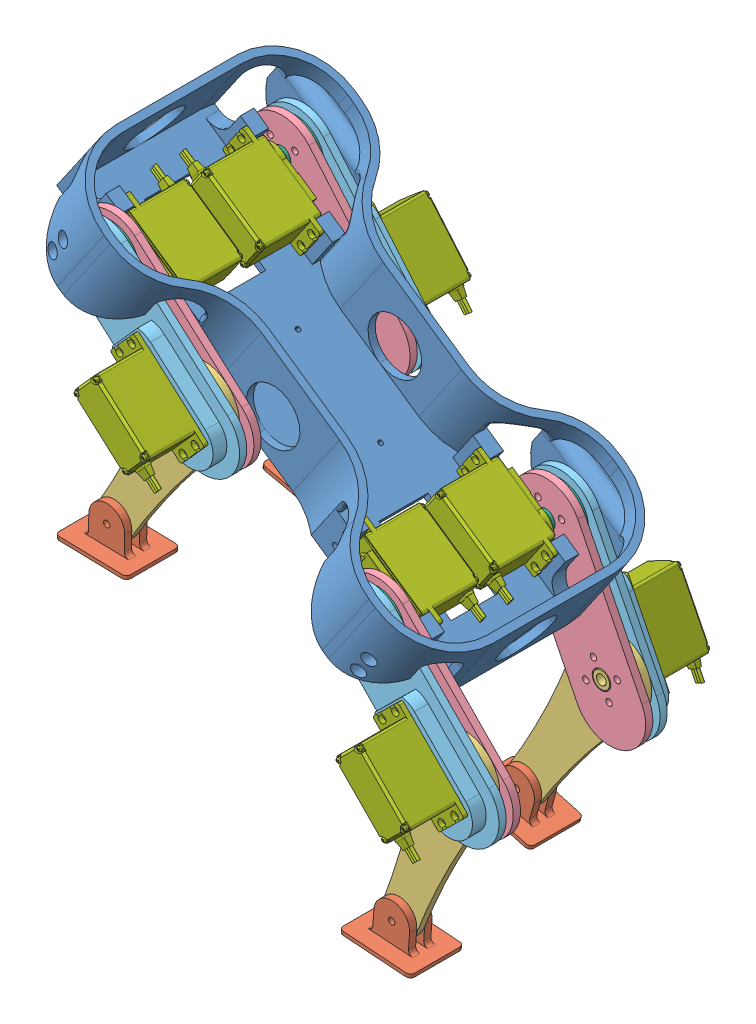
SolidWorks assembly New_Tetrabot, configuration Défaut. Lengths in mm.
Overall size (335.1 322.2 188.63).
33 component instances, 7 part files, 12 mates.
Components (placement in the parent):
- Base2.01-1: Base2.01 [Default] at (233.7736 184.5099 150.2293) x (0.823181 -0.567779 0) z (0 0 1) size (256 46 140)
- New_Leg-1: New_Leg [Défaut] at (201.4507 163.1318 262.4322) x (-0.567779 -0.823181 0) z (-0.823181 0.567779 0) size (142.43 89.83 124.13) (flexible)
  - foot-1: foot [Défaut] at (59.2465 -60.55 -6.6327) x (0 -1 0) z (-0.548618 0 -0.836073) size (30 23 40)
  - New_tibia-1: New_tibia [Default] at (-41.3044 -59.3375 6.9818) x (0.997398 0 -0.072095) z (-0.072095 0 -0.997398) size (119.89 10.06 40.13)
  - New_thigh_2-1: New_thigh_2 [Default] at (-49.8563 -66.2625 75.7966) x (0.121536 0 -0.992587) z (0.992587 0 0.121536) size (120.14 4 40.13)
  - New_thigh-1: New_thigh [Default] at (-49.8563 -58.26 75.7966) x (0.121536 0 -0.992587) z (0.992587 0 0.121536) size (120.14 11.7 40.13)
  - New_adapter-1: New_adapter [Default] at (-49.8563 -62.26 75.7966) x (0.121536 0 -0.992587) z (0.992587 0 0.121536) size (31.75 17.76 31.75)
  - moteur-1: moteur [Défaut] at (-59.7623 -86.9845 65.5096) size (19.88 42.12 58.23)
  - moteur-2: moteur [Défaut] at (-52.3872 -38.613 15.9886) x (0.992587 0 0.121536) z (0.121536 0 -0.992587) size (19.88 42.12 58.23)
- New_Leg-2: New_Leg [Défaut] at (281.8876 228.7822 262.4322) x (0.567779 0.823181 0) z (0.823181 -0.567779 0) size (145.34 89.83 150.19) (flexible)
  - foot-1: foot [Défaut] at (-161.5544 -60.55 172.0564) x (0 -1 0) z (0.507671 0 0.861551) size (30 23 40)
  - New_tibia-1: New_tibia [Default] at (-63.0678 -59.3375 143.8705) x (-0.970756 0 0.24007) z (0.24007 0 0.970756) size (119.89 10.06 40.13)
  - New_thigh_2-1: New_thigh_2 [Default] at (-49.8563 -66.2625 75.7966) x (-0.188751 0 0.982025) z (-0.982025 0 -0.188751) size (120.14 4 40.13)
  - New_thigh-1: New_thigh [Default] at (-49.8563 -58.26 75.7966) x (-0.188751 0 0.982025) z (-0.982025 0 -0.188751) size (120.14 11.7 40.13)
  - New_adapter-1: New_adapter [Default] at (-49.8563 -62.26 75.7966) x (-0.188751 0 0.982025) z (-0.982025 0 -0.188751) size (31.75 17.76 31.75)
  - moteur-1: moteur [Défaut] at (-59.7623 -86.9845 65.5096) size (19.88 42.12 58.23)
  - moteur-2: moteur [Défaut] at (-51.3982 -38.613 135.6382) x (-0.982025 0 -0.188751) z (-0.188751 0 0.982025) size (19.88 42.12 58.23)
- New_Leg-3: New_Leg [Défaut] at (258.5741 244.8624 38.0264) x (0.567779 0.823181 0) z (-0.823181 0.567779 0) size (147.65 89.83 142.79) (flexible)
  - foot-1: foot [Défaut] at (-165.3607 -60.55 -23.8721) x (0 -1 0) z (-0.377394 0 0.926053) size (30 23 40)
  - New_tibia-1: New_tibia [Default] at (-67.8056 -59.3375 8.8158) x (-0.95107 0 -0.308975) z (-0.308975 0 0.95107) size (119.89 10.06 40.13)
  - New_thigh_2-1: New_thigh_2 [Default] at (-49.8563 -66.2625 75.7966) x (-0.260585 0 -0.965451) z (0.965451 0 -0.260585) size (120.14 4 40.13)
  - New_thigh-1: New_thigh [Default] at (-49.8563 -58.26 75.7966) x (-0.260585 0 -0.965451) z (0.965451 0 -0.260585) size (120.14 11.7 40.13)
  - New_adapter-1: New_adapter [Default] at (-49.8563 -62.26 75.7966) x (-0.260585 0 -0.965451) z (0.965451 0 -0.260585) size (31.75 17.76 31.75)
  - moteur-1: moteur [Défaut] at (-59.7623 -86.9845 65.5096) size (19.88 42.12 58.23)
  - moteur-2: moteur [Défaut] at (-74.6887 -38.613 21.3287) x (0.965451 0 -0.260585) z (-0.260585 0 -0.965451) size (19.88 42.12 58.23)
- New_Leg-4: New_Leg [Défaut] at (224.7642 147.0516 38.0264) x (-0.567779 -0.823181 0) z (0.823181 -0.567779 0) size (169.32 89.83 134.03) (flexible)
  - foot-1: foot [Défaut] at (85.5956 -60.55 145.1975) x (0 -1 0) z (0.330473 0 -0.943816) size (30 23 40)
  - New_tibia-1: New_tibia [Default] at (-16.4863 -59.3375 136.5835) x (0.998846 0 0.048021) z (0.048021 0 -0.998846) size (119.89 10.06 40.13)
  - New_thigh_2-1: New_thigh_2 [Default] at (-49.8563 -66.2625 75.7966) x (0.482802 0 0.875729) z (-0.875729 0 0.482802) size (120.14 4 40.13)
  - New_thigh-1: New_thigh [Default] at (-49.8563 -58.26 75.7966) x (0.482802 0 0.875729) z (-0.875729 0 0.482802) size (120.14 11.7 40.13)
  - New_adapter-1: New_adapter [Default] at (-49.8563 -62.26 75.7966) x (0.482802 0 0.875729) z (-0.875729 0 0.482802) size (31.75 17.76 31.75)
  - moteur-1: moteur [Défaut] at (-59.7623 -86.9845 65.5096) size (19.88 42.12 58.23)
  - moteur-2: moteur [Défaut] at (-12.7779 -38.613 122.7923) x (-0.875729 0 0.482802) z (0.482802 0 0.875729) size (19.88 42.12 58.23)
Mates (geometry in assembly coordinates):
- Coincident1: coincident anti-aligned: plane of New_Leg-1/moteur-1 through (170.2074 233.2131 175.4477) normal (-0.567779 -0.823181 0); plane of Base2.01-1 through (236.0447 187.8026 150.2293) normal (0.567779 0.823181 0)
- Concentric1: concentric aligned: circle of New_Leg-1/moteur-1; circle of Base2.01-1
- Coincident2: coincident anti-aligned: plane of New_Leg-1/moteur-1 through (190.012 243.6207 183.9313) normal (0 0 1); plane of Base2.01-1 through (198.5841 237.7082 183.9313) normal (0 0 -1)
- Coincident3: coincident anti-aligned: plane of New_Leg-3/moteur-1 through (170.7161 232.8622 125.0109) normal (-0.567779 -0.823181 0); plane of Base2.01-1 through (236.0447 187.8026 150.2293) normal (0.567779 0.823181 0)
- Concentric4: concentric anti-aligned: circle of New_Leg-3/moteur-1; circle of Base2.01-1
- Coincident4: coincident anti-aligned: plane of New_Leg-3/moteur-1 through (190.5207 243.2698 116.5273) normal (0 0 -1); plane of Base2.01-1 through (198.5841 237.7082 116.5273) normal (0 0 1)
- Concentric5: concentric aligned: circle of New_Leg-4/moteur-1; circle of Base2.01-1
- Coincident5: coincident anti-aligned: plane of New_Leg-4/moteur-1 through (301.3734 142.743 125.0109) normal (-0.567779 -0.823181 0); plane of Base2.01-1 through (236.0447 187.8026 150.2293) normal (0.567779 0.823181 0)
- Coincident6: coincident anti-aligned: plane of New_Leg-4/moteur-1 through (321.1955 153.1385 116.5273) normal (0 0 -1); plane of Base2.01-1 through (337.9852 141.558 116.5273) normal (0 0 1)
- Coincident7: coincident anti-aligned: plane of New_Leg-2/moteur-1 through (301.8821 142.3921 175.4477) normal (-0.567779 -0.823181 0); plane of Base2.01-1 through (236.0447 187.8026 150.2293) normal (0.567779 0.823181 0)
- Concentric6: concentric anti-aligned: circle of New_Leg-2/moteur-1; circle of Base2.01-1
- Coincident8: coincident anti-aligned: plane of New_Leg-2/moteur-1 through (304.5751 164.6022 183.9313) normal (0 0 1); plane of Base2.01-1 through (296.003 170.5147 183.9313) normal (0 0 -1)
